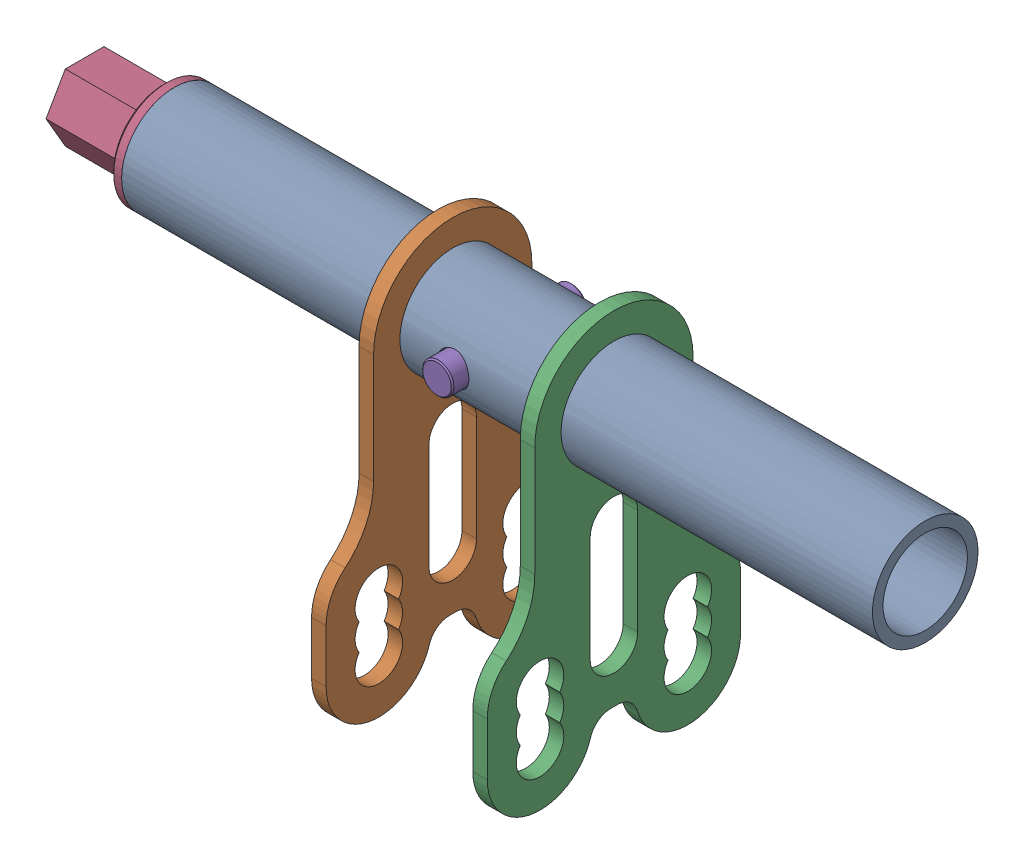
SolidWorks assembly Pinned_Shaft, configuration 默认. Lengths in mm.
Overall size (159.3 75 48).
6 component instances, 4 part files, 3 mates.
Components (placement in the parent):
- TopKart_Shaft-1: TopKart_Shaft [默认] at (-31.3967 25.9787 2.6437) size (142.3 75 48)
  - steering shaft-1: steering shaft [默认] at origin size (142.3 20 20)
  - tie_rod_turner-1: tie_rod_turner [默认] at (14.7 0 0) x (0 0 -1) z (1 0 0) size (48 75 2.75)
  - tie_rod_turner-2: tie_rod_turner [默认] at (45.25 0 0) x (0 0 -1) z (1 0 0) size (48 75 2.75)
- hexagonal shaft-2: hexagonal shaft [默认] at (-66.6967 25.9787 2.6437) x (1 0 0) z (0 -1 -0.001) size (92 20 20)
- Hexagonal_shaft_pin-1: Hexagonal_shaft_pin [Default] at (-3.9967 25.9658 15.5775) x (0.111657 -0.993746 -0.000993) z (-0.993747 -0.111657 -0.000112) size (5.9 25.6 5.9)
Mates (geometry in assembly coordinates):
- Concentric1: concentric aligned: circle of TopKart_Shaft-1/steering shaft-1; circle of hexagonal shaft-2
- Coincident1: coincident anti-aligned: plane of TopKart_Shaft-1/steering shaft-1 through (-66.6967 25.9787 2.6437) normal (-1 0 0); plane of hexagonal shaft-2 through (-66.6967 25.9787 2.6437) normal (1 0 0)
- Concentric4: concentric aligned: cylinder of hexagonal shaft-2 through (-3.9967 25.9887 -7.3562) axis (0 -0.001 1) radius 3.1; circle of Hexagonal_shaft_pin-1
